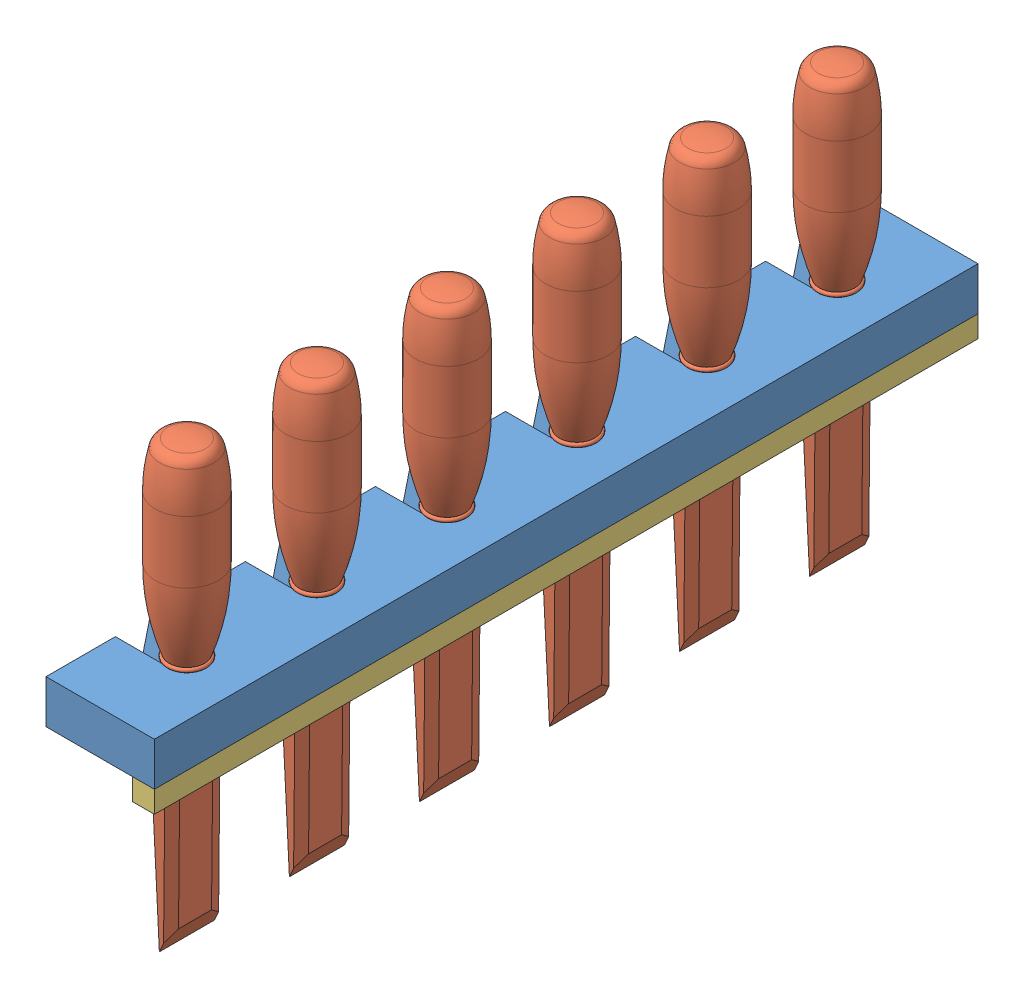
SolidWorks assembly Assem1, configuration Default. Lengths in mm.
Overall size (50 200.03 380).
8 component instances, 3 part files, 21 mates.
Components (placement in the parent):
- Rack-1: Rack [Default] at (55.0505 141.6396 375.9797) size (50 20 380)
- Chisel-1: Chisel [Large] at (55.0505 40.5146 335.9797) x (0 0 -1) z (1 0 0) size (28.96 200.03 28.96)
- Chisel-2: Chisel [Large] at (55.0505 40.5146 215.9797) x (0 0 -1) z (1 0 0) size (28.96 200.03 28.96)
- Chisel-3: Chisel [Large] at (55.0505 40.5146 275.9797) x (0 0 -1) z (1 0 0) size (28.96 200.03 28.96)
- Chisel-4: Chisel [Large] at (55.0505 40.5146 95.9797) x (0 0 -1) z (1 0 0) size (28.96 200.03 28.96)
- Chisel-5: Chisel [Large] at (55.0505 40.5146 35.9797) x (0 0 -1) z (1 0 0) size (28.96 200.03 28.96)
- Chisel-6: Chisel [Large] at (55.0505 40.5146 155.9797) x (0 0 -1) z (1 0 0) size (28.96 200.03 28.96)
- Rack2-1: Rack2 [Default] at (75.0505 126.6396 375.9797) size (10 10 380)
Mates (geometry in assembly coordinates):
- Concentric1: concentric anti-aligned: cylinder of Rack-1 through (55.0505 131.6396 335.9797) axis (0 1 0) radius 8; cone of Chisel-1 through (55.0505 127.5096 335.9797) axis (0 -1 0)
- Coincident3: coincident aligned: plane of Rack-1 through (30.0505 151.6396 -4.0203) normal (0 1 0); circle of Chisel-1
- Parallel8: parallel anti-aligned: line of Rack-1 through (30.0505 131.6396 -4.0203) axis (0 0 1); line of Chisel-1 through (55.0505 40.5146 348.6797) axis (0 0 -1)
- Concentric2: concentric anti-aligned: cylinder of Rack-1 through (55.0505 131.6396 275.9797) axis (0 1 0) radius 8; cone of Chisel-3 through (55.0505 127.5096 275.9797) axis (0 -1 0)
- Concentric3: concentric anti-aligned: cylinder of Rack-1 through (55.0505 131.6396 215.9797) axis (0 1 0) radius 8; cone of Chisel-2 through (55.0505 127.5096 215.9797) axis (0 -1 0)
- Coincident8: coincident aligned: plane of Rack-1 through (30.0505 151.6396 -4.0203) normal (0 1 0); circle of Chisel-3
- Coincident9: coincident aligned: plane of Rack-1 through (30.0505 151.6396 -4.0203) normal (0 1 0); circle of Chisel-2
- Parallel9: parallel anti-aligned: line of Rack-1 through (30.0505 131.6396 -4.0203) axis (0 0 1); line of Chisel-2 through (55.0505 40.5146 228.6797) axis (0 0 -1)
- Parallel10: parallel anti-aligned: line of Rack-1 through (30.0505 131.6396 -4.0203) axis (0 0 1); line of Chisel-3 through (55.0505 40.5146 288.6797) axis (0 0 -1)
- Concentric4: concentric anti-aligned: cylinder of Rack-1 through (55.0505 131.6396 155.9797) axis (0 1 0) radius 8; cone of Chisel-6 through (55.0505 127.5096 155.9797) axis (0 -1 0)
- Concentric5: concentric anti-aligned: cylinder of Rack-1 through (55.0505 131.6396 95.9797) axis (0 1 0) radius 8; cone of Chisel-4 through (55.0505 127.5096 95.9797) axis (0 -1 0)
- Concentric6: concentric anti-aligned: cylinder of Rack-1 through (55.0505 131.6396 35.9797) axis (0 1 0) radius 8; cone of Chisel-5 through (55.0505 127.5096 35.9797) axis (0 -1 0)
- Coincident12: coincident aligned: plane of Rack-1 through (30.0505 151.6396 -4.0203) normal (0 1 0); circle of Chisel-5
- Coincident13: coincident aligned: plane of Rack-1 through (30.0505 151.6396 -4.0203) normal (0 1 0); circle of Chisel-4
- Coincident14: coincident aligned: plane of Rack-1 through (30.0505 151.6396 -4.0203) normal (0 1 0); circle of Chisel-6
- Parallel11: parallel anti-aligned: line of Rack-1 through (30.0505 131.6396 -4.0203) axis (0 0 1); line of Chisel-6 through (55.0505 40.5146 168.6797) axis (0 0 -1)
- Parallel12: parallel anti-aligned: line of Rack-1 through (30.0505 131.6396 -4.0203) axis (0 0 1); line of Chisel-4 through (55.0505 40.5146 108.6797) axis (0 0 -1)
- Parallel13: parallel anti-aligned: line of Rack-1 through (30.0505 131.6396 -4.0203) axis (0 0 1); line of Chisel-5 through (55.0505 40.5146 48.6797) axis (0 0 -1)
- Coincident18: coincident anti-aligned: plane of Rack-1 through (30.0505 131.6396 -4.0203) normal (0 -1 0); plane of Rack2-1 through (70.0505 131.6396 -4.0203) normal (0 1 0)
- Coincident20: coincident aligned: plane of Rack-1 through (55.0505 141.6396 -4.0203) normal (0 0 -1); plane of Rack2-1 through (75.0505 126.6396 -4.0203) normal (0 0 -1)
- Coincident21: coincident aligned: plane of Rack-1 through (80.0505 131.6396 -4.0203) normal (1 0 0); plane of Rack2-1 through (80.0505 121.6396 -4.0203) normal (1 0 0)
